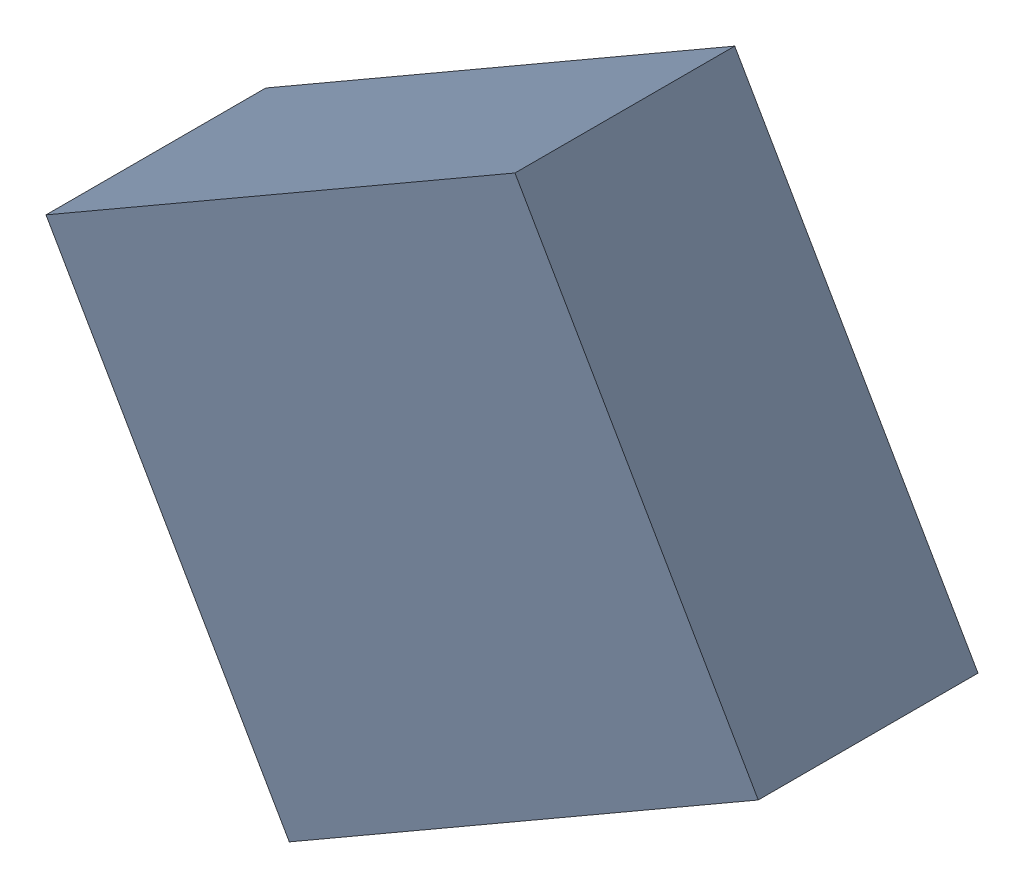
SolidWorks assembly F1_TDA2, configuration Standard. Lengths in mm.
Overall size (4.54 4.41 1.4).
2 component instances, 1 part files, 0 mates.
Components (placement in the parent):
- 885545232-1: 885545232 [Standard] at (46.5047 33.8467 0) size (4.54 4.41 1.4)
  - Extruded_4-1: Extruded_4 [Standard] at origin size (4.54 4.41 1.4)
